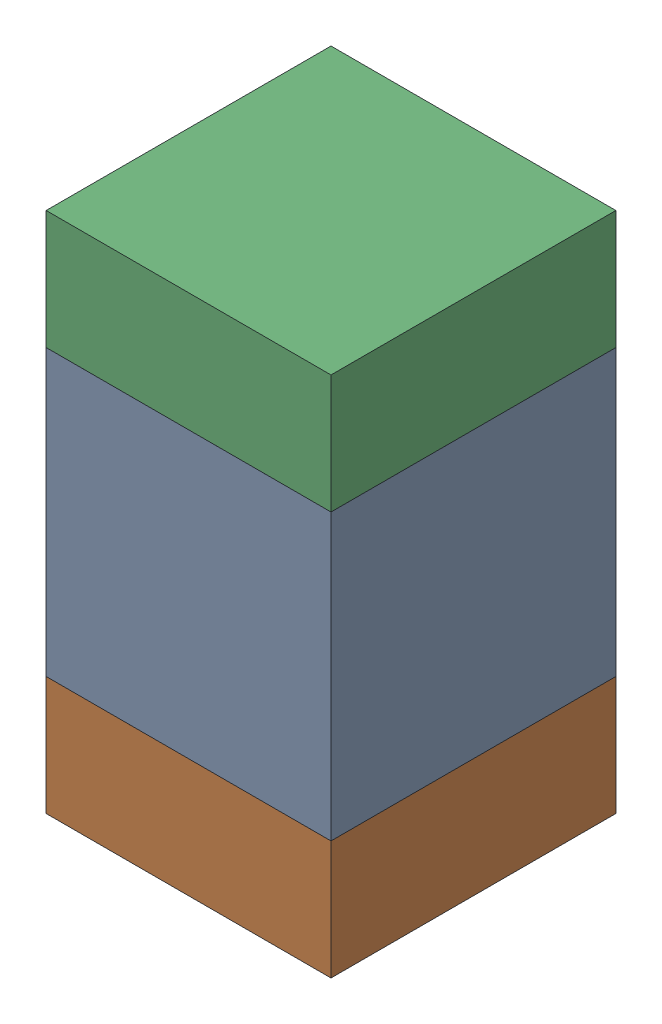
SolidWorks assembly C110_1PCB, configuration Default. Lengths in mm.
Overall size (0.6 1.1 0.6).
6 component instances, 2 part files, 0 mates.
Components (placement in the parent):
- 761606048-1: 761606048 [Default] at (116.7 113.6 0) size (0.6 0.6 0.6)
  - Extruded_9-1: Extruded_9 [Default] at origin size (0.6 0.6 0.6)
- 854785296-1: 854785296 [Default] at (116.7 113.175 0) size (0.6 0.25 0.6)
  - Extruded_10-1: Extruded_10 [Default] at origin size (0.6 0.25 0.6)
- 854785296-2: 854785296 [Default] at (116.7 114.025 0) size (0.6 0.25 0.6)
  - Extruded_10-1: Extruded_10 [Default] at origin size (0.6 0.25 0.6)
